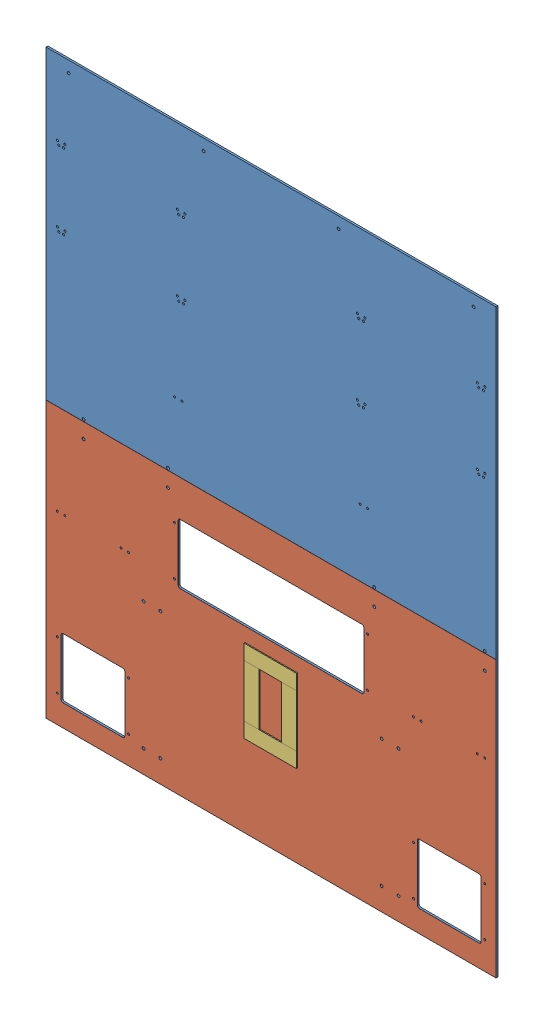
SolidWorks assembly GE-20221, configuration GE-20221_Blue. Lengths in mm.
Overall size (1524 1968.5 9.78).
7 component instances, 3 part files, 12 mates.
Components (placement in the parent):
- GE-20220-1: GE-20220 [GE-20220-Blue] at origin size (1524 1968.5 6.6)
  - GE-20202-1: GE-20202 [Default] at (0 984.25 0) size (1524 1968.5 6.35)
  - GE-20220-Vinyl-1: GE-20220-Vinyl [GE-20220-Blue-Vinyl] at (0 984.25 0.254) size (1524 933.45 0.25)
- Vision_LoadingBay-1: Vision_LoadingBay [Default] at (88.9 330.2 6.604) x (0 1 0) z (0 0 1) size (177.8 50.8 3.17)
- Vision_LoadingBay-2: Vision_LoadingBay [Default] at (-88.9 508 6.604) size (177.8 50.8 3.17)
- Vision_LoadingBay-3: Vision_LoadingBay [Default] at (-88.9 508 6.604) x (0 -1 0) z (0 0 1) size (177.8 50.8 3.17)
- Vision_LoadingBay-4: Vision_LoadingBay [Default] at (-88.9 279.4 6.604) size (177.8 50.8 3.17)
Mates (geometry in assembly coordinates):
- Coincident1: coincident anti-aligned: plane of GE-20220-1/GE-20220-Vinyl-1 through (0 984.25 6.604) normal (0 0 1); plane of Vision_LoadingBay-1 through (-94.2312 330.2 6.604) normal (0 0 -1)
- Coincident2: coincident: plane of Vision_LoadingBay-1 through (88.9 330.2 9.779) normal (0 0 1); plane of Vision_LoadingBay-2 through (-1073.3073 508 9.779) normal (0 0 1)
- Coincident3: coincident: plane of Vision_LoadingBay-2 through (-1073.3073 508 9.779) normal (0 0 1); plane of Vision_LoadingBay-3 through (-88.9 508 9.779) normal (0 0 1)
- Coincident4: coincident aligned: plane of Vision_LoadingBay-3 through (-88.9 508 9.779) normal (0 0 1); plane of Vision_LoadingBay-4 through (-88.9 279.4 9.779) normal (0 0 1)
- Distance1: distance = 279.4 mm aligned: plane of GE-20220-1/GE-20202-1 through (-762 0 6.35) normal (0 -1 0); plane of Vision_LoadingBay-4 through (-88.9 279.4 9.779) normal (0 -1 0)
- Distance2: distance = 88.9 mm: plane of assembly through (0 0 0) normal (1 0 0); plane of assembly; plane of Vision_LoadingBay-4 through (-88.9 279.4 9.779) normal (-1 0 0)
- Coincident7: coincident anti-aligned: plane of Vision_LoadingBay-3 through (-88.9 330.2 9.779) normal (0 -1 0); plane of Vision_LoadingBay-4 through (-88.9 330.2 9.779) normal (0 1 0)
- Coincident8: coincident aligned: plane of Vision_LoadingBay-3 through (-88.9 508 9.779) normal (-1 0 0); plane of Vision_LoadingBay-4 through (-88.9 279.4 9.779) normal (-1 0 0)
- Coincident9: coincident anti-aligned: plane of Vision_LoadingBay-1 through (88.9 330.2 9.779) normal (0 -1 0); plane of Vision_LoadingBay-4 through (-88.9 330.2 9.779) normal (0 1 0)
- Coincident11: coincident aligned: plane of Vision_LoadingBay-1 through (88.9 330.2 9.779) normal (1 0 0); plane of Vision_LoadingBay-4 through (88.9 279.4 9.779) normal (1 0 0)
- Coincident12: coincident: plane of Vision_LoadingBay-2 through (-88.9 508 9.779) normal (0 -1 0); plane of Vision_LoadingBay-3 through (-88.9 508 9.779) normal (0 1 0)
- Coincident13: coincident aligned: plane of Vision_LoadingBay-2 through (-88.9 508 9.779) normal (-1 0 0); plane of Vision_LoadingBay-3 through (-88.9 508 9.779) normal (-1 0 0)
